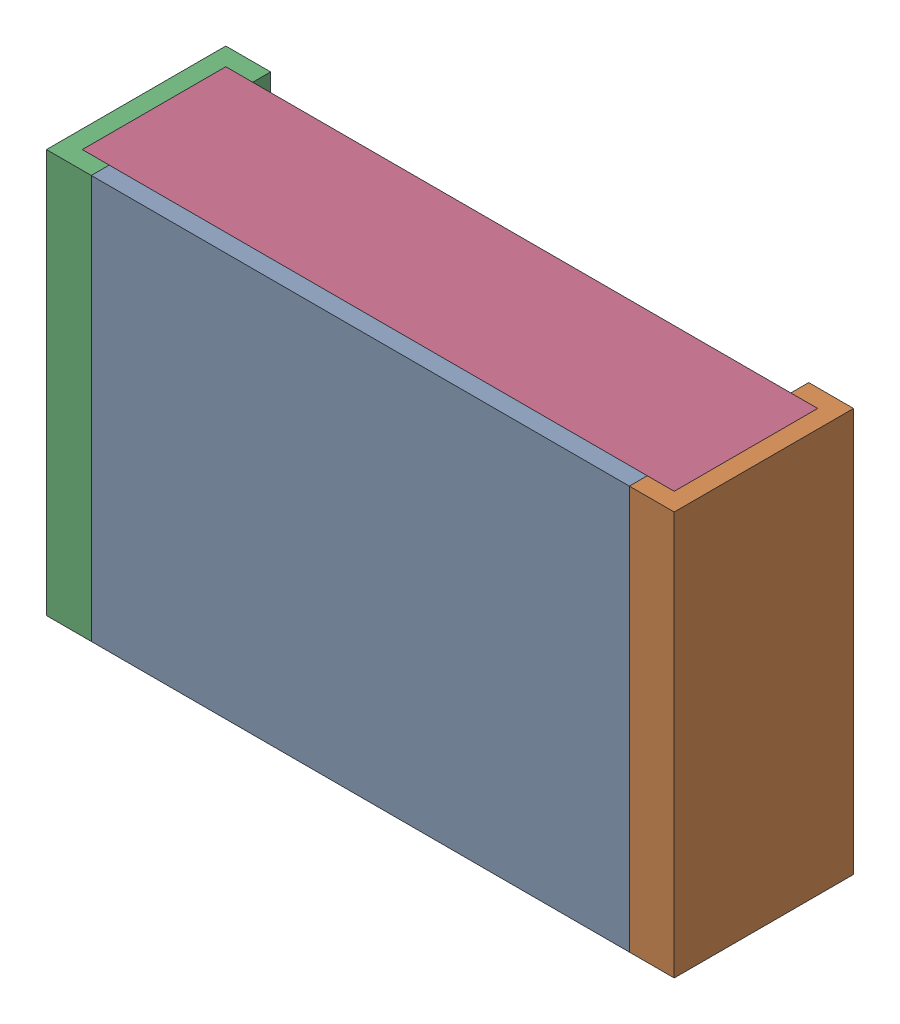
SolidWorks assembly R70, configuration По умолчанию. Lengths in mm.
Overall size (2.1 1.35 0.6).
5 component instances, 3 part files, 0 mates.
Components (placement in the parent):
- RESC2012X06N.step-3-1: RESC2012X06N.step-3 [По умолчанию] at origin size (2.1 1.35 0.6)
  - RESC2012X06N.step-Part-1-1: RESC2012X06N.step-Part-1 [По умолчанию] at (-0.9 -0.675 0.54) size (1.8 1.35 0.06)
  - RESC2012X06N.step-Part-2-1: RESC2012X06N.step-Part-2 [По умолчанию] at (1.05 0.675 0) x (-1 0 0) z (0 0 1) size (0.15 1.35 0.6)
  - RESC2012X06N.step-Part-2-2: RESC2012X06N.step-Part-2 [По умолчанию] at (-1.05 -0.675 0) size (0.15 1.35 0.6)
  - RESC2012X06N.step-Part-3-1: RESC2012X06N.step-Part-3 [По умолчанию] at (-1.05 -0.675 0) size (1.98 1.35 0.48)
